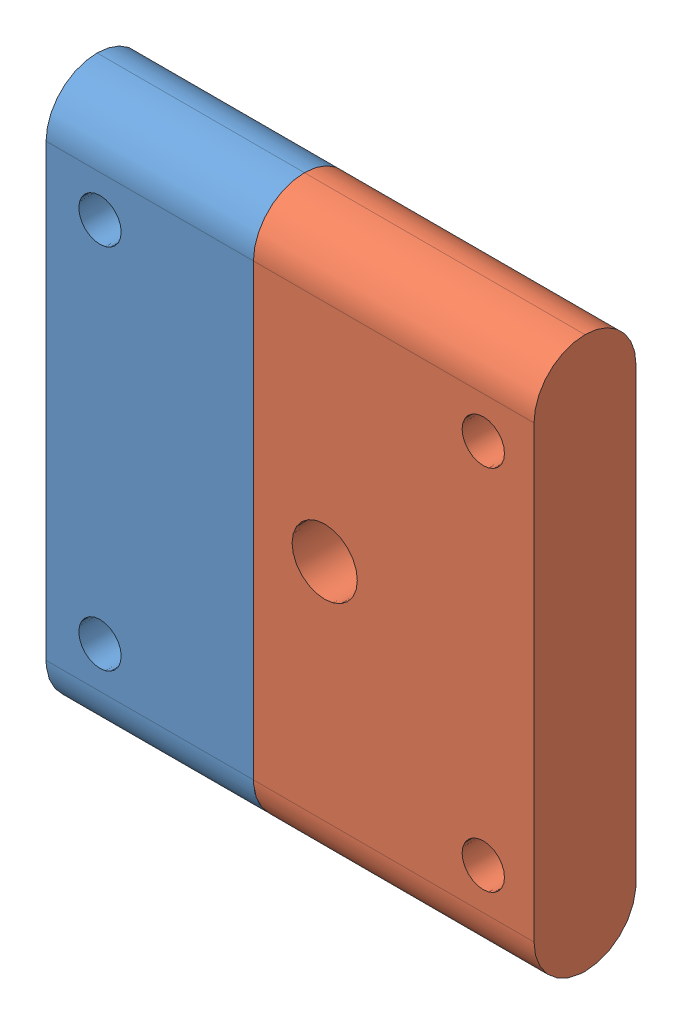
SolidWorks assembly 181226_RotoLock_1, configuration Default. Lengths in mm.
Overall size (76 85.9 15.88).
2 component instances, 2 part files, 3 mates.
Components (placement in the parent):
- 181226_RotoLock_1_Top-1: 181226_RotoLock_1_Top [Default] at origin size (32.3 85.9 15.88)
- 181226_RotoLock_1_Bottom-1: 181226_RotoLock_1_Bottom [Default] at origin size (43.7 85.9 15.88)
Mates (geometry in assembly coordinates):
- Coincident1: coincident: plane of ?; plane of ?
- Coincident2: coincident: line of ?; line of ?
- Coincident3: coincident: point of ?; point of ?
